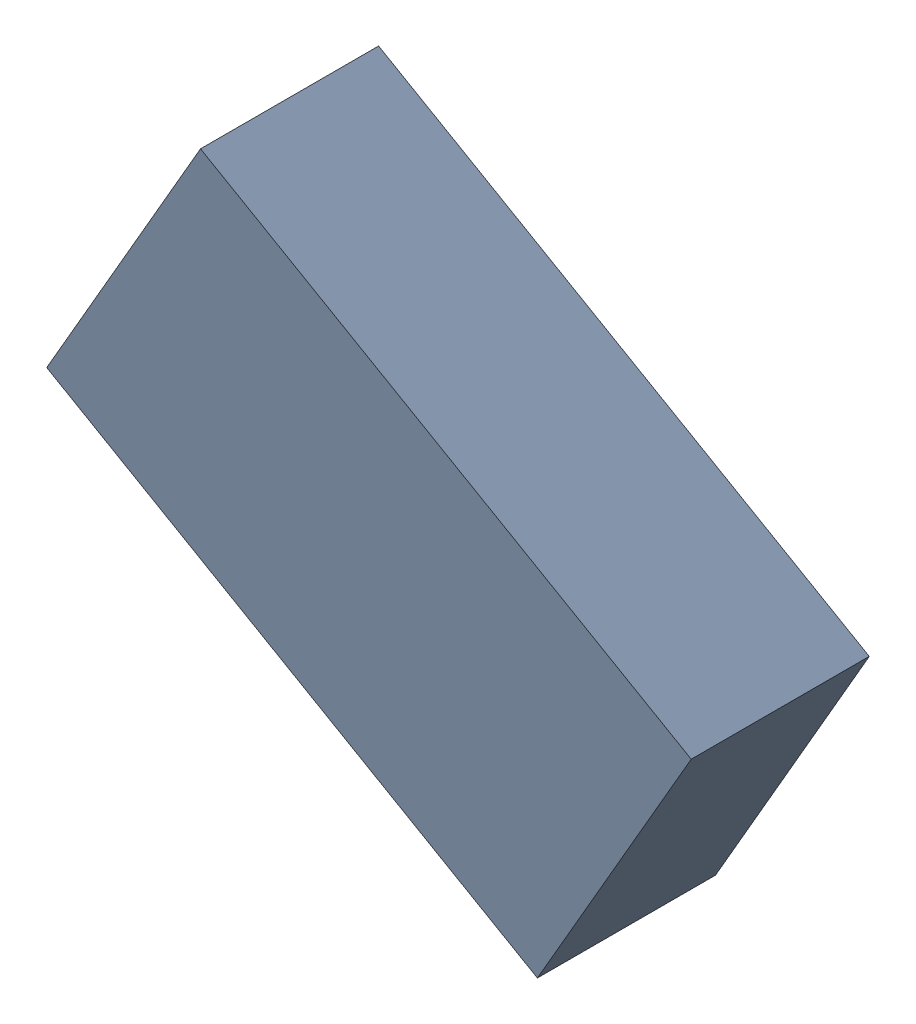
SolidWorks assembly L3_TDA6, configuration Standard. Lengths in mm.
Overall size (1.99 1.7 0.55).
2 component instances, 1 part files, 0 mates.
Components (placement in the parent):
- 885543872-1: 885543872 [Standard] at (-47.8899 34.0246 0) size (1.99 1.7 0.55)
  - Extruded_20-1: Extruded_20 [Standard] at origin size (1.99 1.7 0.55)
